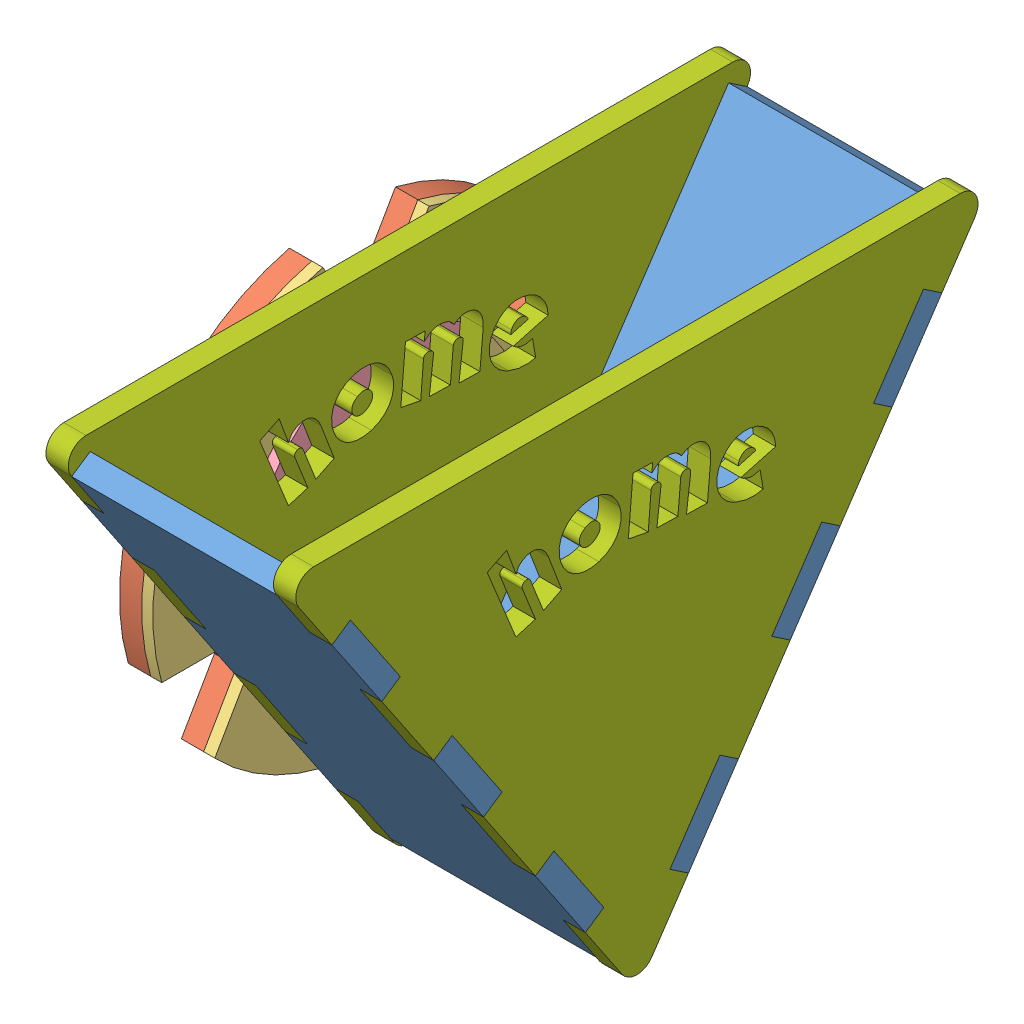
SolidWorks assembly home_piece, configuration Default. Lengths in mm.
Overall size (41.91 73.31 97.13).
16 component instances, 7 part files, 12 mates.
Components (placement in the parent):
- sides-1: sides [Default] at (34.2003 27.0394 2.271) x (0 -0.559193 0.829038) z (-1 0 0) size (3.17 81.25 35.56)
- sides-2: sides [Default] at (34.2003 27.0394 -43.2161) x (0 -0.559193 -0.829038) z (1 0 0) size (3.17 81.25 35.56)
- SLATE_mounts-1: SLATE_mounts [Default] at (19.1277 13.2758 4.4499) x (0 -1 0) z (1 0 0) size (61.68 63.5 6.35)
  - magnetic_mount_back-1: magnetic_mount_back [Default] at (-17.9312 24.9224 -9.0574) size (61.68 63.5 3.17)
  - magnetic_mount_front-1: magnetic_mount_front [Default] at (-17.9312 24.9224 -5.8824) size (61.68 63.5 3.17)
  - connector-1: connector [Default] at (-17.9312 24.9224 -2.7074) x (-0.5 -0.866025 0) z (0 0 -1) size (38.1 38.1 1.59)
  - n72_magnet-1: n72_magnet [Default] at (2.6713 36.8173 -9.0574) size (11.11 11.11 3.17)
  - n72_magnet-2: n72_magnet [Default] at (-17.9312 48.7122 -9.0574) x (0.5 0.866025 0) z (0 0 1) size (11.11 11.11 3.17)
  - n72_magnet-3: n72_magnet [Default] at (-38.5337 36.8173 -9.0574) x (-0.5 0.866025 0) z (0 0 1) size (11.11 11.11 3.17)
  - n72_magnet-4: n72_magnet [Default] at (-38.5337 13.0276 -9.0574) x (-1 0 0) z (0 0 1) size (11.11 11.11 3.17)
  - n72_magnet-5: n72_magnet [Default] at (-17.9312 1.1327 -9.0574) x (-0.5 -0.866025 0) z (0 0 1) size (11.11 11.11 3.17)
  - n72_magnet-6: n72_magnet [Default] at (2.6713 13.0276 -9.0574) x (0.5 -0.866025 0) z (0 0 1) size (11.11 11.11 3.17)
  - d31_magnet-1: d31_magnet [Default] at (-17.9312 24.9224 -4.2949) x (-0.923728 -0.383049 0) z (0 0 -1) size (4.76 4.76 1.59)
  - d31_magnet-2: d31_magnet [Default] at (-17.9312 24.9224 -2.7074) x (-0.923728 -0.383049 0) z (0 0 -1) size (4.76 4.76 1.59)
- front-1: front [Default] at (48.8053 -12.3571 -20.4725) size (3.17 73.31 97.13)
- front-2: front [Default] at (16.4203 -12.3571 -20.4725) size (3.17 73.31 97.13)
Mates (geometry in assembly coordinates):
- Coincident1: coincident aligned: plane of sides-1 through (16.4203 -12.4291 -20.5211) normal (0 -0.559193 0.829038); plane of front-1 through (51.9803 -9.2352 -18.3668) normal (0 -0.559193 0.829038)
- Coincident2: coincident anti-aligned: plane of sides-1 through (51.9803 10.8251 -8.6657) normal (0 0.829038 0.559193); plane of front-1 through (48.8053 9.0496 -6.0335) normal (0 -0.829038 -0.559193)
- Coincident3: coincident aligned: plane of sides-1 through (51.9803 62.957 30.3275) normal (1 0 0); plane of front-1 through (51.9803 60.417 25.5504) normal (1 0 0)
- Coincident4: coincident anti-aligned: plane of sides-2 through (51.9803 -10.6536 -17.7918) normal (0 0.559193 0.829038); plane of front-1 through (48.8053 10.8251 -32.2794) normal (0 -0.559193 -0.829038)
- Coincident5: coincident anti-aligned: plane of sides-2 through (51.9803 0.2963 -25.1776) normal (0 -0.829038 0.559193); plane of front-1 through (48.8053 0.2963 -25.1776) normal (0 0.829038 -0.559193)
- Coincident6: coincident aligned: plane of sides-2 through (51.9803 62.957 -71.2725) normal (1 0 0); plane of front-1 through (51.9803 60.417 25.5504) normal (1 0 0)
- Coincident7: coincident aligned: plane of sides-2 through (16.4203 62.957 -71.2725) normal (-1 0 0); plane of front-2 through (16.4203 60.417 25.5504) normal (-1 0 0)
- Coincident8: coincident anti-aligned: plane of sides-2 through (16.4203 43.2537 -54.1528) normal (0 -0.829038 0.559193); plane of front-2 through (16.4203 43.2537 -54.1528) normal (0 0.829038 -0.559193)
- Coincident9: coincident anti-aligned: plane of sides-2 through (51.9803 -10.6536 -17.7918) normal (0 0.559193 0.829038); plane of front-2 through (16.4203 53.7825 -61.2545) normal (0 -0.559193 -0.829038)
- Coincident10: coincident anti-aligned: plane of SLATE_mounts-1/connector-1 through (16.4203 31.207 -20.4725) normal (1 0 0); plane of front-2 through (16.4203 60.417 25.5504) normal (-1 0 0)
- Tangent1: tangent aligned: cylinder of SLATE_mounts-1/magnetic_mount_front-1 through (14.8328 31.207 -20.4725) axis (-1 0 0) radius 31.75; plane of front-2 through (19.5953 62.957 25.5504) normal (0 1 0)
- Coincident11: coincident anti-aligned: plane of SLATE_mounts-1/magnetic_mount_back-1; plane of front-1 through (48.8053 -12.3571 -20.4725) normal (0 0 1)
